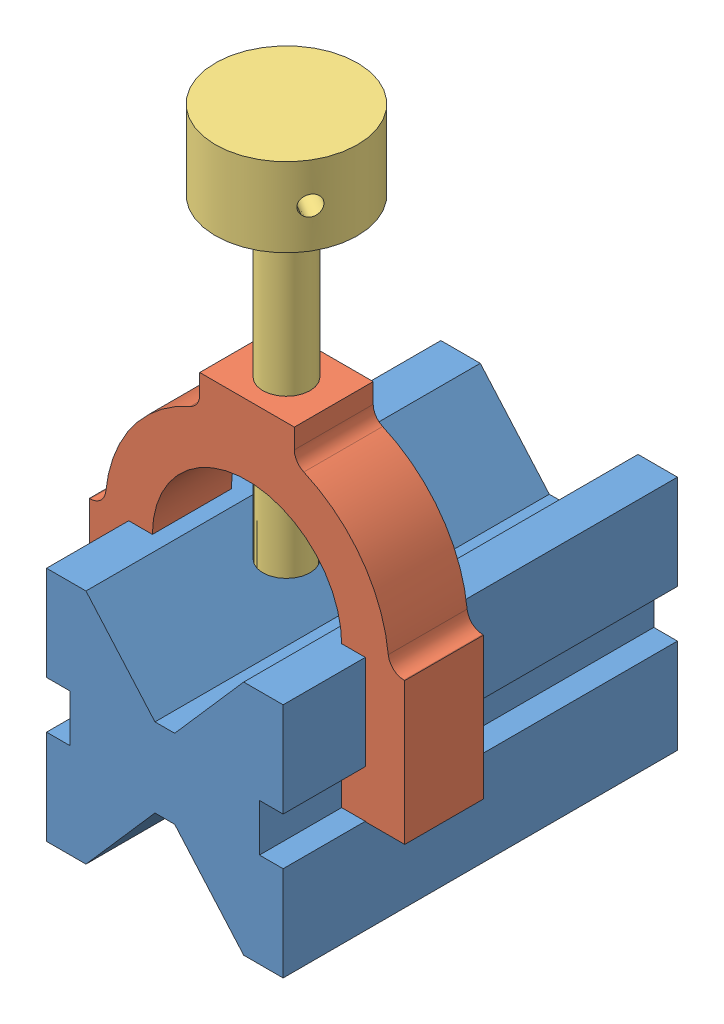
SolidWorks assembly Montaj1, configuration Varsayılan. Lengths in mm.
Overall size (80 161.57 100).
3 component instances, 3 part files, 5 mates.
Components (placement in the parent):
- alt_parca-1: alt_parca [Varsayılan] at (-29.3803 -33.5117 50) size (60 60 100)
- rurucu-1: rurucu [Varsayılan] at (0.6197 26.3967 109.1608) size (80 77.66 20)
- cubuk-1: cubuk [Varsayılan] at (-2.4743 48.2925 124.3015) x (0 1 0) z (-0.856784 0 -0.515675) size (100 36 36)
Mates (geometry in assembly coordinates):
- Genişlik1: width: rurucu-1, alt_parca-1
- Genişlik3: width: alt_parca-1, rurucu-1
- Uzaklık1: distance: alt_parca-1, rurucu-1
- Eş Merkezli2: concentric: rurucu-1, cubuk-1
- Uzaklık2: distance: cubuk-1, rurucu-1
